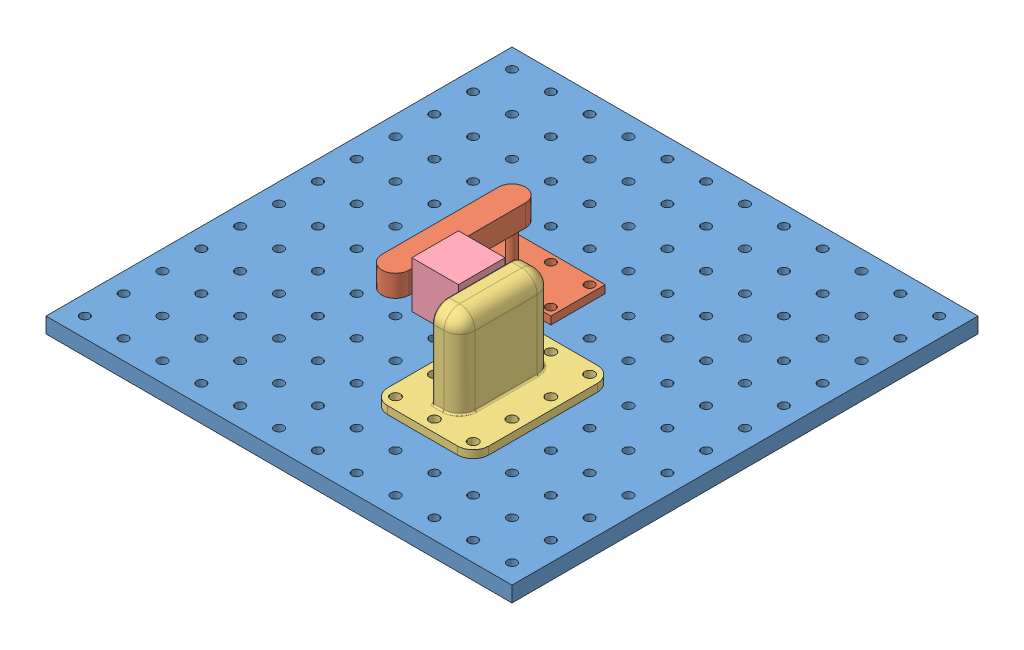
SolidWorks assembly ASM3_v3, configuration 기본. Lengths in mm.
Overall size (300 73.5 300).
4 component instances, 4 part files, 10 mates.
Components (placement in the parent):
- platform-1: platform [기본] at (-708.9249 -138.0932 300) size (300 10 300)
- finger_model-1: finger_model [기본] at (-721.4249 -128.0932 287.5) size (60 55 113.75)
- gripper_side-1: gripper_side [기본] at (-671.4249 -128.0932 337.5) size (65 60 90)
- object-1: object [기본] at (-695.1749 -94.5932 348.2362) size (32.5 30 30)
Mates (geometry in assembly coordinates):
- 동심1: concentric aligned: cylinder of platform-1 through (-696.4249 -128.0932 287.5) axis (0 -1 0) radius 3; cylinder of finger_model-1 through (-696.4249 -123.0932 287.5) axis (0 -1 0) radius 3
- 동심2: concentric aligned: cylinder of platform-1 through (-746.4249 -128.0932 287.5) axis (0 -1 0) radius 3; cylinder of finger_model-1 through (-746.4249 -123.0932 287.5) axis (0 -1 0) radius 3
- 일치1: coincident anti-aligned: plane of platform-1 through (-708.9249 -128.0932 300) normal (0 1 0); plane of finger_model-1 through (-721.4249 -128.0932 287.5) normal (0 -1 0)
- 일치2: coincident anti-aligned: plane of platform-1 through (-708.9249 -128.0932 300) normal (0 1 0); plane of gripper_side-1 through (-671.4249 -128.0932 337.5) normal (0 -1 0)
- 동심4: concentric aligned: cylinder of platform-1 through (-646.4249 -128.0932 312.5) axis (0 -1 0) radius 3; cylinder of gripper_side-1 through (-646.4249 -123.0932 312.5) axis (0 -1 0) radius 3.2
- 동심5: concentric aligned: cylinder of platform-1 through (-696.4249 -128.0932 387.5) axis (0 -1 0) radius 3; cylinder of gripper_side-1 through (-696.4249 -123.0932 387.5) axis (0 -1 0) radius 3.2
- 일치3: coincident anti-aligned: plane of gripper_side-1 through (-680.1749 54.4068 320) normal (-1 0 0); plane of object-1 through (-680.1749 -64.5932 333.2362) normal (1 0 0)
- 탄젠트2: tangent anti-aligned: plane of finger_model-1 through (-712.6749 -87.0932 287.5) normal (1 0 0); sphere of object-1
- 평행1: parallel anti-aligned: plane of platform-1 through (-708.9249 -128.0932 300) normal (0 1 0); plane of object-1 through (-695.1749 -94.5932 348.2362) normal (0 -1 0)
- 탄젠트4: tangent aligned: plane of finger_model-1 through (-721.4249 -73.0932 287.5) normal (0 1 0); sphere of object-1
